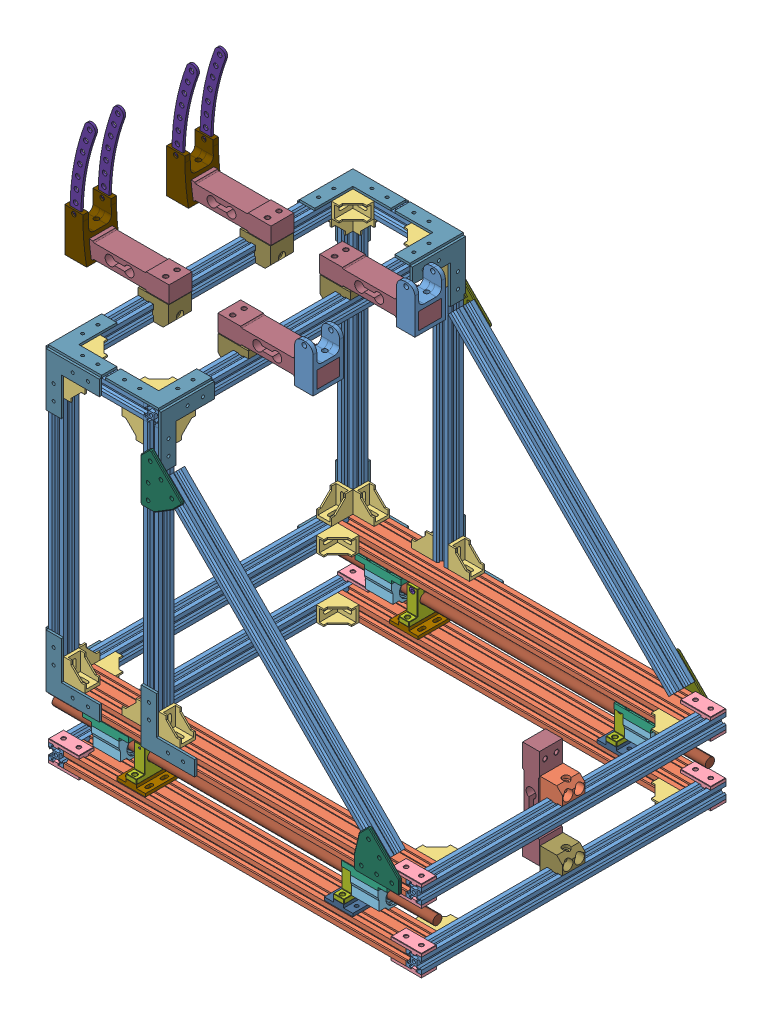
SolidWorks assembly Balança, configuration Valor predeterminado. Lengths in mm.
Overall size (580.64 644.02 408).
129 component instances, 20 part files, 104 mates.
Components (placement in the parent):
- Quadrado_400x490mm-1: Quadrado_400x490mm [Valor predeterminado] at (337.6063 -443.954 467.9915) size (490 20 400)
  - Perfil_20x20mm-3: Perfil_20x20mm [400mm] at (-555.9529 400 -177.9915) x (1 0 0) z (0 -1 0) size (20 400 20)
  - Perfil_20x40mm-2: Perfil_20x40mm [450mm] at (-545.9529 400 -147.9915) x (0 0 -1) z (0 -1 0) size (40 450 20)
  - Perfil_20x40mm-3: Perfil_20x40mm [450mm] at (-545.9529 400 212.0085) x (0 0 -1) z (0 -1 0) size (40 450 20)
  - Perfil_20x20mm-4: Perfil_20x20mm [400mm] at (-85.9529 400 -177.9915) x (1 0 0) z (0 -1 0) size (20 400 20)
  - Cantoneira_interna_20x20mm-1: Cantoneira_interna_20x20mm [Default] at (-95.9529 390 182.0085) x (0 1 0) z (0 0 1) size (20 28 28)
  - Cantoneira_interna_20x20mm-2: Cantoneira_interna_20x20mm [Default] at (-95.9529 410 -137.9915) x (0 -1 0) z (0 0 -1) size (20 28 28)
  - Cantoneira_interna_20x20mm-3: Cantoneira_interna_20x20mm [Default] at (-545.9529 390 -137.9915) x (0 1 0) z (0 0 -1) size (20 28 28)
  - Cantoneira_interna_20x20mm-4: Cantoneira_interna_20x20mm [Default] at (-545.9529 410 182.0085) x (0 -1 0) z (0 0 1) size (20 28 28)
- Quadrado_400x490mm-2: Quadrado_400x490mm [Valor predeterminado] at (337.6063 -364.954 467.9915) size (490 20 400)
  - Perfil_20x20mm-3: Perfil_20x20mm [400mm] at (-555.9529 400 -177.9915) x (1 0 0) z (0 -1 0) size (20 400 20)
  - Perfil_20x40mm-2: Perfil_20x40mm [450mm] at (-545.9529 400 -147.9915) x (0 0 -1) z (0 -1 0) size (40 450 20)
  - Perfil_20x40mm-3: Perfil_20x40mm [450mm] at (-545.9529 400 212.0085) x (0 0 -1) z (0 -1 0) size (40 450 20)
  - Perfil_20x20mm-4: Perfil_20x20mm [400mm] at (-85.9529 400 -177.9915) x (1 0 0) z (0 -1 0) size (20 400 20)
  - Cantoneira_interna_20x20mm-1: Cantoneira_interna_20x20mm [Default] at (-95.9529 390 182.0085) x (0 1 0) z (0 0 1) size (20 28 28)
  - Cantoneira_interna_20x20mm-2: Cantoneira_interna_20x20mm [Default] at (-95.9529 410 -137.9915) x (0 -1 0) z (0 0 -1) size (20 28 28)
  - Cantoneira_interna_20x20mm-3: Cantoneira_interna_20x20mm [Default] at (-545.9529 390 -137.9915) x (0 1 0) z (0 0 -1) size (20 28 28)
  - Cantoneira_interna_20x20mm-4: Cantoneira_interna_20x20mm [Default] at (-545.9529 410 182.0085) x (0 -1 0) z (0 0 1) size (20 28 28)
- Cantoneira_Plana_impressa_20x40mm-17: Cantoneira_Plana_impressa_20x40mm [Valor predeterminado] at (241.6534 -33.954 680) x (0 0 -1) z (1 0 0) size (20 6 40)
- Cantoneira_Plana_impressa_20x40mm-18: Cantoneira_Plana_impressa_20x40mm [Valor predeterminado] at (241.6534 45.046 680) x (0 0 -1) z (1 0 0) size (20 6 40)
- Cantoneira_Plana_impressa_20x40mm-19: Cantoneira_Plana_impressa_20x40mm [Valor predeterminado] at (241.6534 25.046 680) x (0 0 1) z (1 0 0) size (20 6 40)
- Cantoneira_Plana_impressa_20x40mm-20: Cantoneira_Plana_impressa_20x40mm [Valor predeterminado] at (241.6534 -53.954 680) x (0 0 1) z (1 0 0) size (20 6 40)
- Pillow_Block_SC12UU-1: Pillow_Block_SC12UU [Default] at (186.6534 13.046 669) x (0 0 -1) z (1 0 0) size (42 28 36)
- Adaptador_para_Pillow_Block_SC12UU-2: Adaptador_para_Pillow_Block_SC12UU [Valor predeterminado] at (186.6534 17.046 669) size (60 12.59 42.39)
- Suporte_SK12-1: Suporte_SK12 [Valor predeterminado] at (110.9034 -7.9702 663.3047) x (0 0 -1) z (1 0 0) size (42 37.6 14)
  - Shaft support SK12-1: Shaft support SK12 [Valor predeterminado] at (-5.6953 6.0163 42) size (42 37.5 14)
  - m4x16-2: m4x16 [Valor predeterminado] at (4.3047 16.0441 42) x (-1 0 0) z (0 0.924225 0.381849) size (20 7 7)
- Suporte_SK12-3: Suporte_SK12 [Valor predeterminado] at (194.9034 -7.9702 316.6953) x (0 0 1) z (-1 0 0) size (42 37.6 14)
  - Shaft support SK12-1: Shaft support SK12 [Valor predeterminado] at (-5.6953 6.0163 42) size (42 37.5 14)
  - m4x16-2: m4x16 [Valor predeterminado] at (4.3047 16.0441 42) x (-1 0 0) z (0 0.924225 0.381849) size (20 7 7)
- Suporte_SK12-4: Suporte_SK12 [Valor predeterminado] at (-161.5966 -7.9702 663.3047) x (0 0 -1) z (1 0 0) size (42 37.6 14)
  - Shaft support SK12-1: Shaft support SK12 [Valor predeterminado] at (-5.6953 6.0163 42) size (42 37.5 14)
  - m4x16-2: m4x16 [Valor predeterminado] at (4.3047 16.0441 42) x (-1 0 0) z (0 0.924225 0.381849) size (20 7 7)
- Suporte_SK12-5: Suporte_SK12 [Valor predeterminado] at (-77.5966 -7.9702 316.6953) x (0 0 1) z (-1 0 0) size (42 37.6 14)
  - Shaft support SK12-1: Shaft support SK12 [Valor predeterminado] at (-5.6953 6.0163 42) size (42 37.5 14)
  - m4x16-2: m4x16 [Valor predeterminado] at (4.3047 16.0441 42) x (-1 0 0) z (0 0.924225 0.381849) size (20 7 7)
- Adaptador_para_Suporte_SK12_movel-1: Adaptador_para_Suporte_SK12_movel [Valor predeterminado] at (-119.5966 -33.954 669) size (37.5 9 42)
- Adaptador_para_Suporte_SK12_movel-2: Adaptador_para_Suporte_SK12_movel [Valor predeterminado] at (-119.5966 -33.954 311) size (37.5 9 42)
- Adaptador_para_Suporte_SK12_fixo-1: Adaptador_para_Suporte_SK12_fixo [Valor predeterminado] at (152.9034 -33.954 669) size (37.5 9 42)
- Adaptador_para_Suporte_SK12_fixo-3: Adaptador_para_Suporte_SK12_fixo [Valor predeterminado] at (152.9034 -33.954 311) size (37.5 9 42)
- Eixo_Linear_12mm-1: Eixo_Linear_12mm [500mm] at (11.6534 -1.954 669) x (0 -0.455727 -0.89012) z (1 0 0) size (12 12 500)
- Pillow_Block_SC12UU-2: Pillow_Block_SC12UU [Default] at (-153.3466 13.046 669) x (0 0 -1) z (1 0 0) size (42 28 36)
- Pillow_Block_SC12UU-3: Pillow_Block_SC12UU [Default] at (186.6534 13.046 311) x (0 0 1) z (-1 0 0) size (42 28 36)
- Pillow_Block_SC12UU-4: Pillow_Block_SC12UU [Default] at (-153.3466 13.046 311) x (0 0 1) z (-1 0 0) size (42 28 36)
- Adaptador_para_Pillow_Block_SC12UU-3: Adaptador_para_Pillow_Block_SC12UU [Valor predeterminado] at (-153.3466 17.046 669) x (-1 0 0) z (0 0 -1) size (60 12.59 42.39)
- Adaptador_para_Pillow_Block_SC12UU-4: Adaptador_para_Pillow_Block_SC12UU [Valor predeterminado] at (-153.3466 17.046 311) x (-1 0 0) z (0 0 -1) size (60 12.59 42.39)
- Adaptador_para_Pillow_Block_SC12UU-5: Adaptador_para_Pillow_Block_SC12UU [Valor predeterminado] at (186.6534 17.046 311) size (60 12.59 42.39)
- Perfil_20x20mm-1: Perfil_20x20mm [350mm] at (-218.3466 45.046 680) size (20 350 20)
- Perfil_20x20mm-2: Perfil_20x20mm [105mm] at (-103.3466 405.046 680) x (0 1 0) z (0 0 1) size (20 105 20)
- Perfil_20x20mm-3: Perfil_20x20mm [350mm] at (-93.3466 45.046 680) size (20 350 20)
- Perfil_20x20mm-7: Perfil_20x20mm [400mm] at (-218.3466 405.046 290) x (0 1 0) z (1 0 0) size (20 400 20)
- Cantoneira_interna_20x20mm-1: Cantoneira_interna_20x20mm [Default] at (-208.3466 395.046 670) x (0 1 0) z (-1 0 0) size (20 28 28)
- Cantoneira_interna_20x20mm-2: Cantoneira_interna_20x20mm [Default] at (-208.3466 395.046 670) x (0 0 1) z (0 1 0) size (20 28 28)
- Cantoneira_interna_20x20mm-3: Cantoneira_interna_20x20mm [Default] at (-208.3466 395.046 670) x (-1 0 0) z (0 0 1) size (20 28 28)
- Cantoneira_interna_20x20mm-20: Cantoneira_interna_20x20mm [Default] at (-83.3466 45.046 690) x (0 0 -1) z (0 -1 0) size (20 28 28)
- Suporte_para_Celula_de_Carga_Reforcado-1: Suporte_para_Celula_de_Carga_Reforcado [Valor predeterminado] at (-207.1035 412.2907 571.8983) x (0 0 -1) z (1 0 0) size (30 30 40)
- Celula_de_Carga_20kg-1: Celula_de_Carga_20kg [Default] at (-252.8466 436.046 571.8983) x (0 0 -1) z (1 0 0) size (30 22 130)
- Cantoneira_plana_lateral-1: Cantoneira_plana_lateral [Valor predeterminado] at (-228.3466 415.046 693) x (0 0 -1) z (-1 0 0) size (3 70 70)
- Cantoneira_plana_lateral-9: Cantoneira_plana_lateral [Valor predeterminado] at (-228.3466 418.046 690) x (0 -1 0) z (0 0 1) size (3 70 70)
- Cantoneira_plana_lateral-10: Cantoneira_plana_lateral [Valor predeterminado] at (-228.3466 415.046 690) x (-1 0 0) z (0 0 1) size (3 70 70)
- Cantoneira_plana_lateral-19: Cantoneira_plana_lateral [Valor predeterminado] at (-103.3466 25.046 690) x (0 0 1) z (-1 0 0) size (3 70 70)
- Placa_Lateral_45graus_impressa_esquerda-1: Placa_Lateral_45graus_impressa_esquerda [Default] at (254.8514 25.046 690) x (0 0 1) z (-1 0 0) size (6 57.44 60)
- Placa_Lateral_45graus_impressa_esquerda-2: Placa_Lateral_45graus_impressa_esquerda [Default] at (-103.3466 383.2441 690) x (0 0 1) z (0.707107 -0.707107 0) size (6 57.44 60)
- Perfil_20x20mm-10: Perfil_20x20mm [410mm] at (213.6382 52.1171 680) x (0.707107 0.707107 0) z (0 0 1) size (20 410 20)
- Placa_Lateral_45graus_impressa_direita-1: Placa_Lateral_45graus_impressa_direita [Default] at (254.8514 25.046 286) x (0 0 1) z (-1 0 0) size (6 57.44 60)
- Placa_Lateral_45graus_impressa_direita-2: Placa_Lateral_45graus_impressa_direita [Default] at (-103.3466 383.2441 286) x (0 0 1) z (0.707107 -0.707107 0) size (6 57.44 60)
- Montagem_Encaixe_Celula_de_Angulo_Variavel-1: Montagem_Encaixe_Celula_de_Angulo_Variavel [Valor predeterminado] at (-305.8466 447.046 556.8983) x (0 0 1) z (-1 0 0) size (44 166.02 40.37) (flexible)
  - Peça_de_angulo-1: Peça_de_angulo [Default] at (0 51.2431 -0.1062) x (1 0 0) z (0 0.169603 0.985512) size (3 125.28 19.4)
  - Peça_Central-1: Peça_Central [Default] at origin size (44 57 28.72)
  - Peça_de_angulo-2: Peça_de_angulo [Default] at (-37 51.2431 -0.1062) x (1 0 0) z (0 0.169603 0.985512) size (3 125.28 19.4)
- Encaixe_Celula_de_Angulo_Fixo-1: Encaixe_Celula_de_Angulo_Fixo [Default] at (-5.8466 447.046 556.8983) x (0 0 -1) z (1 0 0) size (40 57 24)
- Perfil_20x20mm-11: Perfil_20x20mm [350mm] at (-218.3466 45.046 300) size (20 350 20)
- Perfil_20x20mm-12: Perfil_20x20mm [350mm] at (-93.3466 45.046 300) size (20 350 20)
- Perfil_20x20mm-13: Perfil_20x20mm [105mm] at (-103.3466 405.046 300) x (0 1 0) z (0 0 1) size (20 105 20)
- Eixo_Linear_12mm-3: Eixo_Linear_12mm [500mm] at (11.6534 -1.954 311) x (0 -0.455727 0.89012) z (-1 0 0) size (12 12 500)
- Cantoneira_interna_20x20mm-21: Cantoneira_interna_20x20mm [Default] at (-83.3466 395.046 670) x (-1 0 0) z (0 0 1) size (20 28 28)
- Cantoneira_interna_20x20mm-22: Cantoneira_interna_20x20mm [Default] at (-103.3466 415.046 670) x (0 -1 0) z (1 0 0) size (20 28 28)
- Cantoneira_interna_20x20mm-23: Cantoneira_interna_20x20mm [Default] at (-103.3466 395.046 690) x (0 0 -1) z (0 1 0) size (20 28 28)
- Cantoneira_interna_20x20mm-24: Cantoneira_interna_20x20mm [Default] at (-228.3466 395.046 310) x (1 0 0) z (0 0 -1) size (20 28 28)
- Cantoneira_interna_20x20mm-25: Cantoneira_interna_20x20mm [Default] at (-208.3466 415.046 310) x (0 -1 0) z (-1 0 0) size (20 28 28)
- Cantoneira_interna_20x20mm-26: Cantoneira_interna_20x20mm [Default] at (-208.3466 395.046 290) x (0 0 1) z (0 1 0) size (20 28 28)
- Cantoneira_interna_20x20mm-27: Cantoneira_interna_20x20mm [Default] at (-103.3466 395.046 310) x (0 1 0) z (1 0 0) size (20 28 28)
- Cantoneira_interna_20x20mm-28: Cantoneira_interna_20x20mm [Default] at (-103.3466 395.046 310) x (0 0 -1) z (0 1 0) size (20 28 28)
- Cantoneira_interna_20x20mm-29: Cantoneira_interna_20x20mm [Default] at (-103.3466 395.046 310) x (1 0 0) z (0 0 -1) size (20 28 28)
- Cantoneira_interna_20x20mm-30: Cantoneira_interna_20x20mm [Default] at (-208.3466 45.046 690) x (0 0 -1) z (0 -1 0) size (20 28 28)
- Cantoneira_interna_20x20mm-31: Cantoneira_interna_20x20mm [Default] at (-103.3466 45.046 670) x (0 0 1) z (0 -1 0) size (20 28 28)
- Cantoneira_interna_20x20mm-32: Cantoneira_interna_20x20mm [Default] at (-228.3466 45.046 670) size (20 28 28)
- Cantoneira_interna_20x20mm-33: Cantoneira_interna_20x20mm [Default] at (-208.3466 45.046 310) x (-1 0 0) z (0 0 -1) size (20 28 28)
- Cantoneira_interna_20x20mm-34: Cantoneira_interna_20x20mm [Default] at (-208.3466 45.046 310) x (0 0 -1) z (0 -1 0) size (20 28 28)
- Cantoneira_interna_20x20mm-35: Cantoneira_interna_20x20mm [Default] at (-103.3466 45.046 290) x (0 0 1) z (0 -1 0) size (20 28 28)
- Cantoneira_interna_20x20mm-36: Cantoneira_interna_20x20mm [Default] at (-83.3466 45.046 310) x (0 0 -1) z (0 -1 0) size (20 28 28)
- Perfil_20x20mm-14: Perfil_20x20mm [400mm] at (-93.3466 405.046 290) x (0 1 0) z (1 0 0) size (20 400 20)
- Cantoneira_Plana_impressa_20x40mm-21: Cantoneira_Plana_impressa_20x40mm [Valor predeterminado] at (241.6534 45.046 300) x (0 0 -1) z (1 0 0) size (20 6 40)
- Cantoneira_Plana_impressa_20x40mm-22: Cantoneira_Plana_impressa_20x40mm [Valor predeterminado] at (241.6534 25.046 300) x (0 0 1) z (1 0 0) size (20 6 40)
- Cantoneira_Plana_impressa_20x40mm-23: Cantoneira_Plana_impressa_20x40mm [Valor predeterminado] at (-208.3466 25.046 680) x (0 0 -1) z (-1 0 0) size (20 6 40)
- Cantoneira_Plana_impressa_20x40mm-24: Cantoneira_Plana_impressa_20x40mm [Valor predeterminado] at (-208.3466 25.046 300) x (0 0 -1) z (-1 0 0) size (20 6 40)
- Cantoneira_Plana_impressa_20x40mm-25: Cantoneira_Plana_impressa_20x40mm [Valor predeterminado] at (-208.3466 -33.954 680) x (0 0 1) z (-1 0 0) size (20 6 40)
- Cantoneira_Plana_impressa_20x40mm-26: Cantoneira_Plana_impressa_20x40mm [Valor predeterminado] at (-208.3466 -53.954 680) x (0 0 -1) z (-1 0 0) size (20 6 40)
- Cantoneira_Plana_impressa_20x40mm-27: Cantoneira_Plana_impressa_20x40mm [Valor predeterminado] at (241.6534 -33.954 300) x (0 0 -1) z (1 0 0) size (20 6 40)
- Cantoneira_Plana_impressa_20x40mm-28: Cantoneira_Plana_impressa_20x40mm [Valor predeterminado] at (241.6534 -53.954 300) x (0 0 1) z (1 0 0) size (20 6 40)
- Cantoneira_Plana_impressa_20x40mm-29: Cantoneira_Plana_impressa_20x40mm [Valor predeterminado] at (-208.3466 -53.954 300) x (0 0 -1) z (-1 0 0) size (20 6 40)
- Cantoneira_Plana_impressa_20x40mm-30: Cantoneira_Plana_impressa_20x40mm [Valor predeterminado] at (-208.3466 -33.954 300) x (0 0 1) z (-1 0 0) size (20 6 40)
- Suporte_para_Celula_de_Carga_Reforcado-2: Suporte_para_Celula_de_Carga_Reforcado [Valor predeterminado] at (-104.5898 412.2907 541.8983) x (0 0 1) z (-1 0 0) size (30 30 40)
- Suporte_para_Celula_de_Carga_Reforcado-3: Suporte_para_Celula_de_Carga_Reforcado [Valor predeterminado] at (-207.1035 412.2907 438.1017) x (0 0 -1) z (1 0 0) size (30 30 40)
- Suporte_para_Celula_de_Carga_Reforcado-4: Suporte_para_Celula_de_Carga_Reforcado [Valor predeterminado] at (-104.5898 412.2907 408.1017) x (0 0 1) z (-1 0 0) size (30 30 40)
- Celula_de_Carga_20kg-2: Celula_de_Carga_20kg [Default] at (-58.8466 436.046 571.8983) x (0 0 -1) z (1 0 0) size (30 22 130)
- Celula_de_Carga_20kg-3: Celula_de_Carga_20kg [Default] at (-252.8466 436.046 408.1017) x (0 0 1) z (-1 0 0) size (30 22 130)
- Celula_de_Carga_20kg-4: Celula_de_Carga_20kg [Default] at (-58.8466 436.046 408.1017) x (0 0 1) z (-1 0 0) size (30 22 130)
- Cantoneira_plana_lateral-20: Cantoneira_plana_lateral [Valor predeterminado] at (-228.3466 415.046 290) x (0 0 -1) z (-1 0 0) size (3 70 70)
- Cantoneira_plana_lateral-21: Cantoneira_plana_lateral [Valor predeterminado] at (-228.3466 25.046 690) x (0 0 1) z (-1 0 0) size (3 70 70)
- Cantoneira_plana_lateral-22: Cantoneira_plana_lateral [Valor predeterminado] at (-228.3466 25.046 287) x (0 0 1) z (-1 0 0) size (3 70 70)
- Cantoneira_plana_lateral-23: Cantoneira_plana_lateral [Valor predeterminado] at (-83.3466 415.046 690) x (0 1 0) z (0 0 1) size (3 70 70)
- Cantoneira_plana_lateral-24: Cantoneira_plana_lateral [Valor predeterminado] at (-80.3466 415.046 690) x (-1 0 0) z (0 0 1) size (3 70 70)
- Cantoneira_plana_lateral-25: Cantoneira_plana_lateral [Valor predeterminado] at (-231.3466 415.046 290) x (1 0 0) z (0 0 -1) size (3 70 70)
- Cantoneira_plana_lateral-26: Cantoneira_plana_lateral [Valor predeterminado] at (-228.3466 415.046 290) x (0 1 0) z (0 0 -1) size (3 70 70)
- Cantoneira_plana_lateral-27: Cantoneira_plana_lateral [Valor predeterminado] at (-83.3466 415.046 290) x (1 0 0) z (0 0 -1) size (3 70 70)
- Cantoneira_plana_lateral-28: Cantoneira_plana_lateral [Valor predeterminado] at (-83.3466 418.046 290) x (0 -1 0) z (0 0 -1) size (3 70 70)
- Cantoneira_plana_lateral-29: Cantoneira_plana_lateral [Valor predeterminado] at (-231.3466 25.046 690) size (3 70 70)
- Cantoneira_plana_lateral-30: Cantoneira_plana_lateral [Valor predeterminado] at (-228.3466 25.046 290) x (-1 0 0) z (0 0 -1) size (3 70 70)
- Cantoneira_plana_lateral-31: Cantoneira_plana_lateral [Valor predeterminado] at (-103.3466 25.046 287) x (0 0 1) z (-1 0 0) size (3 70 70)
- Perfil_20x20mm-15: Perfil_20x20mm [410mm] at (213.6382 52.1171 300) x (0.707107 0.707107 0) z (0 0 1) size (20 410 20)
- Montagem_Encaixe_Celula_de_Angulo_Variavel-2: Montagem_Encaixe_Celula_de_Angulo_Variavel [Valor predeterminado] at (-305.8466 447.046 423.1017) x (0 0 1) z (-1 0 0) size (44 166.02 40.37) (flexible)
  - Peça_de_angulo-1: Peça_de_angulo [Default] at (0 51.2431 -0.1062) x (1 0 0) z (0 0.169603 0.985512) size (3 125.28 19.4)
  - Peça_Central-1: Peça_Central [Default] at origin size (44 57 28.72)
  - Peça_de_angulo-2: Peça_de_angulo [Default] at (-37 51.2431 -0.1062) x (1 0 0) z (0 0.169603 0.985512) size (3 125.28 19.4)
- Encaixe_Celula_de_Angulo_Fixo-4: Encaixe_Celula_de_Angulo_Fixo [Default] at (-5.8466 447.046 423.1017) x (0 0 -1) z (1 0 0) size (40 57 24)
- Celula_de_Carga_20kg-5: Celula_de_Carga_20kg [Default] at (220.6534 27.546 475) x (0 0 1) z (0 1 0) size (30 22 130)
- Suporte_para_Celula_de_Carga_Reforcado_ajustavel-2: Suporte_para_Celula_de_Carga_Reforcado_ajustavel [Valor predeterminado] at (244.4087 46.2892 505) x (0 0 -1) z (0 1 0) size (30 30 60)
- Suporte_para_Celula_de_Carga_Reforcado-11: Suporte_para_Celula_de_Carga_Reforcado [Valor predeterminado] at (244.4087 -32.7108 505) x (0 0 -1) z (0 1 0) size (30 30 40)
Mates (geometry in assembly coordinates):
- Coincidente11: coincident aligned: plane of Quadrado_400x490mm-1/Perfil_20x40mm-3 through (241.6534 -33.954 690) normal (0 0 1); plane of Adaptador_para_Suporte_SK12_fixo-1 through (152.9034 -28.954 690) normal (0 0 1)
- Coincidente21: coincident anti-aligned: plane of Quadrado_400x490mm-1/Perfil_20x40mm-3 through (241.6534 -33.954 690) normal (0 1 0); plane of Adaptador_para_Suporte_SK12_fixo-1 through (152.9034 -33.954 669) normal (0 -1 0)
- Distância11: distance = 70 mm anti-aligned: plane of Adaptador_para_Suporte_SK12_fixo-1 through (171.6534 -28.954 669) normal (1 0 0); plane of Quadrado_400x490mm-1/Perfil_20x20mm-4 through (241.6534 -43.954 690) normal (-1 0 0)
- Coincidente51: coincident anti-aligned: plane of Adaptador_para_Suporte_SK12_fixo-1 through (152.9034 -24.954 669) normal (0 1 0); plane of Suporte_SK12-1/Shaft support SK12-1 through (145.9034 -24.954 669) normal (0 -1 0)
- Coincidente91: coincident anti-aligned: plane of Quadrado_400x490mm-1/Perfil_20x40mm-3 through (241.6534 -33.954 676) normal (0 1 0); plane of Adaptador_para_Suporte_SK12_movel-1 through (-119.5966 -33.954 669) normal (0 -1 0)
- Concêntrico11: concentric anti-aligned: cylinder of Suporte_SK12-4/Shaft support SK12-1 through (-126.5966 -1.954 669) axis (1 0 0) radius 6; cylinder of Eixo_Linear_12mm-1 through (261.6534 -1.954 669) axis (-1 0 0) radius 6
- Coincidente111: coincident aligned: plane of Quadrado_400x490mm-1/Perfil_20x20mm-4 through (261.6534 -43.954 690) normal (1 0 0); plane of Eixo_Linear_12mm-1 through (261.6534 -1.954 669) normal (1 0 0)
- Concêntrico31: concentric anti-aligned: cylinder of Eixo_Linear_12mm-1 through (261.6534 -1.954 669) axis (-1 0 0) radius 6; cylinder of Pillow_Block_SC12UU-1 through (216.9287 -1.954 669) axis (1 0 0) radius 6
- Coincidente141: coincident anti-aligned: plane of Pillow_Block_SC12UU-1 through (204.6534 13.046 658) normal (0 1 0); plane of Adaptador_para_Pillow_Block_SC12UU-2 through (186.6534 13.046 669) normal (0 -1 0)
- Concêntrico61: concentric anti-aligned: circle of Pillow_Block_SC12UU-1; cylinder of Adaptador_para_Pillow_Block_SC12UU-2 through (173.6534 25.046 684.25) axis (0 -1 0) radius 2.8
- Concêntrico71: concentric anti-aligned: cylinder of Pillow_Block_SC12UU-1 through (199.6534 13.046 653.75) axis (0 1 0) radius 2.5; cylinder of Adaptador_para_Pillow_Block_SC12UU-2 through (199.6534 25.046 653.75) axis (0 -1 0) radius 2.8
- Coincidente151: coincident aligned: plane of Adaptador_para_Pillow_Block_SC12UU-2 through (186.6534 25.046 690) normal (0 0 1); plane of Quadrado_400x490mm-2/Perfil_20x40mm-3 through (241.6534 45.046 690) normal (0 0 1)
- Coincidente161: coincident aligned: plane of Adaptador_para_Pillow_Block_SC12UU-5 through (186.6534 25.046 290) normal (0 0 -1); plane of Quadrado_400x490mm-2/Perfil_20x40mm-2 through (241.6534 45.046 290) normal (0 0 -1)
- Coincidente171: coincident anti-aligned: plane of Adaptador_para_Pillow_Block_SC12UU-3 through (-153.3466 25.046 669) normal (0 1 0); plane of Quadrado_400x490mm-2/Perfil_20x40mm-3 through (241.6534 25.046 676) normal (0 -1 0)
- Concêntrico91: concentric aligned: cylinder of Adaptador_para_Suporte_SK12_fixo-1 through (152.9034 -28.954 685) axis (0 -1 0) radius 2.8; cylinder of Suporte_SK12-1/Shaft support SK12-1 through (152.9034 12.547 685) axis (0 -1 0) radius 2.75
- Coincidente211: coincident aligned: plane of Quadrado_400x490mm-2/Perfil_20x40mm-3 through (241.6534 45.046 690) normal (0 0 1); plane of Perfil_20x20mm-1 through (-218.3466 395.046 690) normal (0 0 1)
- Coincidente221: coincident aligned: plane of Quadrado_400x490mm-2/Perfil_20x20mm-3 through (-228.3466 35.046 690) normal (-1 0 0); plane of Perfil_20x20mm-1 through (-228.3466 395.046 680) normal (-1 0 0)
- Coincidente231: coincident anti-aligned: plane of Quadrado_400x490mm-2/Perfil_20x20mm-3 through (-218.3466 45.046 690) normal (0 1 0); plane of Perfil_20x20mm-1 through (-218.3466 45.046 680) normal (0 -1 0)
- Coincidente35: coincident aligned: plane of Perfil_20x20mm-1 through (-218.3466 395.046 690) normal (0 0 1); plane of Perfil_20x20mm-2 through (-208.3466 405.046 690) normal (0 0 1)
- Coincidente36: coincident aligned: plane of Perfil_20x20mm-2 through (-208.3466 405.046 690) normal (0 0 1); plane of Perfil_20x20mm-3 through (-93.3466 395.046 690) normal (0 0 1)
- Coincidente38: coincident anti-aligned: plane of Perfil_20x20mm-2 through (-103.3466 405.046 680) normal (1 0 0); plane of Perfil_20x20mm-3 through (-103.3466 395.046 680) normal (-1 0 0)
- Coincidente40: coincident anti-aligned: plane of Perfil_20x20mm-1 through (-208.3466 395.046 680) normal (1 0 0); plane of Perfil_20x20mm-2 through (-208.3466 405.046 680) normal (-1 0 0)
- Coincidente42: coincident aligned: plane of Perfil_20x20mm-1 through (-228.3466 395.046 680) normal (-1 0 0); plane of Perfil_20x20mm-7 through (-228.3466 405.046 690) normal (-1 0 0)
- Coincidente43: coincident aligned: plane of Perfil_20x20mm-1 through (-218.3466 395.046 690) normal (0 0 1); plane of Perfil_20x20mm-7 through (-218.3466 405.046 690) normal (0 0 1)
- Coincidente232: coincident aligned: plane of Perfil_20x20mm-7 through (-218.3466 415.046 690) normal (0 1 0); plane of Cantoneira_interna_20x20mm-1 through (-208.3466 415.046 670) normal (0 1 0)
- Coincidente233: coincident anti-aligned: plane of Perfil_20x20mm-7 through (-208.3466 405.046 690) normal (1 0 0); plane of Cantoneira_interna_20x20mm-1 through (-208.3466 415.046 670) normal (-1 0 0)
- Coincidente234: coincident anti-aligned: plane of Perfil_20x20mm-2 through (-208.3466 405.046 670) normal (0 0 -1); plane of Cantoneira_interna_20x20mm-1 through (-208.3466 415.046 670) normal (0 0 1)
- Coincidente236: coincident aligned: plane of Perfil_20x20mm-1 through (-218.3466 395.046 690) normal (0 0 1); plane of Cantoneira_interna_20x20mm-2 through (-208.3466 395.046 690) normal (0 0 1)
- Coincidente237: coincident anti-aligned: plane of Perfil_20x20mm-1 through (-208.3466 395.046 680) normal (1 0 0); plane of Cantoneira_interna_20x20mm-2 through (-208.3466 395.046 690) normal (-1 0 0)
- Coincidente238: coincident anti-aligned: plane of Perfil_20x20mm-2 through (-208.3466 395.046 680) normal (0 -1 0); plane of Cantoneira_interna_20x20mm-2 through (-208.3466 395.046 690) normal (0 1 0)
- Coincidente240: coincident anti-aligned: plane of Perfil_20x20mm-1 through (-218.3466 395.046 670) normal (0 0 -1); plane of Cantoneira_interna_20x20mm-3 through (-228.3466 395.046 670) normal (0 0 1)
- Coincidente241: coincident anti-aligned: plane of Perfil_20x20mm-7 through (-218.3466 395.046 690) normal (0 -1 0); plane of Cantoneira_interna_20x20mm-3 through (-228.3466 395.046 670) normal (0 1 0)
- Coincidente242: coincident aligned: plane of Perfil_20x20mm-7 through (-228.3466 405.046 690) normal (-1 0 0); plane of Cantoneira_interna_20x20mm-3 through (-228.3466 395.046 670) normal (-1 0 0)
- Coincidente243: coincident anti-aligned: plane of Quadrado_400x490mm-2/Perfil_20x40mm-3 through (241.6534 45.046 690) normal (0 1 0); plane of Cantoneira_interna_20x20mm-20 through (-83.3466 45.046 670) normal (0 -1 0)
- Coincidente244: coincident anti-aligned: plane of Perfil_20x20mm-3 through (-83.3466 395.046 680) normal (1 0 0); plane of Cantoneira_interna_20x20mm-20 through (-83.3466 45.046 670) normal (-1 0 0)
- Coincidente245: coincident aligned: plane of Perfil_20x20mm-3 through (-93.3466 395.046 690) normal (0 0 1); plane of Cantoneira_interna_20x20mm-20 through (-83.3466 45.046 690) normal (0 0 1)
- Coincidente246: coincident anti-aligned: plane of Perfil_20x20mm-1 through (-218.3466 395.046 680) normal (0 1 0); plane of Perfil_20x20mm-7 through (-218.3466 395.046 690) normal (0 -1 0)
- Coincidente247: coincident aligned: plane of Perfil_20x20mm-2 through (-208.3466 415.046 680) normal (0 1 0); plane of Perfil_20x20mm-7 through (-218.3466 415.046 690) normal (0 1 0)
- Coincidente248: coincident anti-aligned: plane of Perfil_20x20mm-2 through (-208.3466 395.046 680) normal (0 -1 0); plane of Perfil_20x20mm-3 through (-93.3466 395.046 680) normal (0 1 0)
- Coincidente256: coincident aligned: plane of Cantoneira_Plana_impressa_20x40mm-18 through (261.6534 49.046 690) normal (1 0 0); plane of Quadrado_400x490mm-2/Perfil_20x20mm-4 through (261.6534 35.046 690) normal (1 0 0)
- Coincidente257: coincident anti-aligned: plane of Quadrado_400x490mm-2/Perfil_20x40mm-3 through (241.6534 45.046 690) normal (0 1 0); plane of Cantoneira_Plana_impressa_20x40mm-18 through (241.6534 45.046 680) normal (0 -1 0)
- Coincidente258: coincident aligned: plane of Quadrado_400x490mm-2/Perfil_20x40mm-3 through (241.6534 45.046 690) normal (0 0 1); plane of Cantoneira_Plana_impressa_20x40mm-18 through (221.6534 49.046 690) normal (0 0 1)
- Distância33: distance = 25 mm anti-aligned: plane of Adaptador_para_Pillow_Block_SC12UU-2 through (216.6534 25.046 669) normal (1 0 0); plane of Quadrado_400x490mm-2/Perfil_20x20mm-4 through (241.6534 35.046 690) normal (-1 0 0)
- Coincidente261: coincident aligned: plane of Quadrado_400x490mm-1/Perfil_20x20mm-4 through (261.6534 -43.954 690) normal (1 0 0); plane of Quadrado_400x490mm-2/Perfil_20x20mm-4 through (261.6534 35.046 690) normal (1 0 0)
- Coincidente268: coincident aligned: plane of Quadrado_400x490mm-2/Perfil_20x20mm-4 through (261.6534 35.046 690) normal (1 0 0); plane of Cantoneira_Plana_impressa_20x40mm-19 through (261.6534 21.046 670) normal (1 0 0)
- Coincidente269: coincident aligned: plane of Quadrado_400x490mm-2/Perfil_20x40mm-3 through (241.6534 31.046 690) normal (0 0 1); plane of Cantoneira_Plana_impressa_20x40mm-19 through (221.6534 21.046 690) normal (0 0 1)
- Coincidente270: coincident anti-aligned: plane of Quadrado_400x490mm-2/Perfil_20x40mm-3 through (241.6534 25.046 690) normal (0 -1 0); plane of Cantoneira_Plana_impressa_20x40mm-19 through (241.6534 25.046 680) normal (0 1 0)
- Coincidente271: coincident aligned: plane of Quadrado_400x490mm-1/Perfil_20x40mm-3 through (241.6534 -33.954 690) normal (0 0 1); plane of Cantoneira_Plana_impressa_20x40mm-17 through (221.6534 -29.954 690) normal (0 0 1)
- Coincidente272: coincident aligned: plane of Quadrado_400x490mm-1/Perfil_20x40mm-3 through (241.6534 -47.954 690) normal (0 0 1); plane of Cantoneira_Plana_impressa_20x40mm-20 through (221.6534 -57.954 690) normal (0 0 1)
- Coincidente273: coincident aligned: plane of Quadrado_400x490mm-1/Perfil_20x20mm-4 through (261.6534 -43.954 690) normal (1 0 0); plane of Cantoneira_Plana_impressa_20x40mm-20 through (261.6534 -57.954 670) normal (1 0 0)
- Coincidente274: coincident aligned: plane of Quadrado_400x490mm-1/Perfil_20x20mm-4 through (261.6534 -43.954 690) normal (1 0 0); plane of Cantoneira_Plana_impressa_20x40mm-17 through (261.6534 -29.954 690) normal (1 0 0)
- Coincidente275: coincident anti-aligned: plane of Quadrado_400x490mm-1/Perfil_20x40mm-3 through (241.6534 -33.954 690) normal (0 1 0); plane of Cantoneira_Plana_impressa_20x40mm-17 through (241.6534 -33.954 680) normal (0 -1 0)
- Coincidente276: coincident anti-aligned: plane of Quadrado_400x490mm-1/Perfil_20x40mm-3 through (241.6534 -53.954 690) normal (0 -1 0); plane of Cantoneira_Plana_impressa_20x40mm-20 through (241.6534 -53.954 680) normal (0 1 0)
- Coincidente277: coincident anti-aligned: plane of Perfil_20x20mm-7 through (-208.3466 405.046 690) normal (1 0 0); plane of Suporte_para_Celula_de_Carga_Reforcado-1 through (-208.3466 412.2907 541.8983) normal (-1 0 0)
- Coincidente278: coincident anti-aligned: plane of Perfil_20x20mm-7 through (-218.3466 415.046 690) normal (0 1 0); plane of Suporte_para_Celula_de_Carga_Reforcado-1 through (-207.1035 415.046 541.8983) normal (0 -1 0)
- Concêntrico93: concentric aligned: cylinder of Suporte_para_Celula_de_Carga_Reforcado-1 through (-199.8466 395.045 564.3983) axis (0 1 0) radius 3.25; cylinder of Celula_de_Carga_20kg-1 through (-199.8466 425.046 564.3983) axis (0 1 0) radius 2.75
- Concêntrico94: concentric aligned: cylinder of Suporte_para_Celula_de_Carga_Reforcado-1 through (-199.8466 395.045 549.3983) axis (0 1 0) radius 3.25; cylinder of Celula_de_Carga_20kg-1 through (-199.8466 425.046 549.3983) axis (0 1 0) radius 2.75
- Coincidente279: coincident anti-aligned: plane of Suporte_para_Celula_de_Carga_Reforcado-1 through (-207.1035 425.046 541.8983) normal (0 1 0); plane of Celula_de_Carga_20kg-1 through (-252.8466 425.046 541.8983) normal (0 -1 0)
- Concêntrico95: concentric aligned: cylinder of Suporte_SK12-4/Shaft support SK12-1 through (-119.5966 12.547 685) axis (0 -1 0) radius 2.75; cylinder of Adaptador_para_Suporte_SK12_movel-1 through (-119.5966 -28.954 685) axis (0 -1 0) radius 2.8
- Concêntrico96: concentric aligned: cylinder of Suporte_SK12-4/Shaft support SK12-1 through (-119.5966 12.547 653) axis (0 -1 0) radius 2.75; cylinder of Adaptador_para_Suporte_SK12_movel-1 through (-119.5966 -28.954 653) axis (0 -1 0) radius 2.8
- Coincidente280: coincident anti-aligned: plane of Perfil_20x20mm-2 through (-208.3466 405.046 690) normal (0 0 1); plane of Cantoneira_plana_lateral-1 through (-228.3466 415.046 690) normal (0 0 -1)
- Coincidente281: coincident aligned: plane of Perfil_20x20mm-2 through (-208.3466 415.046 680) normal (0 1 0); plane of Cantoneira_plana_lateral-1 through (-228.3466 415.046 690) normal (0 1 0)
- Coincidente282: coincident aligned: plane of Perfil_20x20mm-7 through (-228.3466 405.046 690) normal (-1 0 0); plane of Cantoneira_plana_lateral-1 through (-228.3466 415.046 690) normal (-1 0 0)
- Coincidente283: coincident anti-aligned: plane of Perfil_20x20mm-7 through (-218.3466 415.046 690) normal (0 1 0); plane of Cantoneira_plana_lateral-9 through (-228.3466 415.046 690) normal (0 -1 0)
- Coincidente284: coincident aligned: plane of Perfil_20x20mm-2 through (-208.3466 405.046 690) normal (0 0 1); plane of Cantoneira_plana_lateral-9 through (-228.3466 415.046 690) normal (0 0 1)
- Coincidente285: coincident aligned: plane of Perfil_20x20mm-7 through (-228.3466 405.046 690) normal (-1 0 0); plane of Cantoneira_plana_lateral-9 through (-228.3466 415.046 690) normal (-1 0 0)
- Coincidente288: coincident anti-aligned: plane of Perfil_20x20mm-7 through (-228.3466 405.046 690) normal (-1 0 0); plane of Cantoneira_plana_lateral-10 through (-228.3466 415.046 690) normal (1 0 0)
- Coincidente289: coincident aligned: plane of Perfil_20x20mm-7 through (-218.3466 415.046 690) normal (0 1 0); plane of Cantoneira_plana_lateral-10 through (-231.3466 415.046 690) normal (0 1 0)
- Coincidente290: coincident aligned: plane of Perfil_20x20mm-1 through (-218.3466 395.046 690) normal (0 0 1); plane of Cantoneira_plana_lateral-10 through (-231.3466 415.046 690) normal (0 0 1)
- Coincidente291: coincident anti-aligned: plane of Quadrado_400x490mm-2/Perfil_20x40mm-3 through (241.6534 45.046 690) normal (0 0 1); plane of Cantoneira_plana_lateral-19 through (-103.3466 25.046 690) normal (0 0 -1)
- Coincidente292: coincident aligned: plane of Perfil_20x20mm-3 through (-103.3466 395.046 680) normal (-1 0 0); plane of Cantoneira_plana_lateral-19 through (-103.3466 25.046 693) normal (-1 0 0)
- Coincidente293: coincident aligned: plane of Quadrado_400x490mm-2/Perfil_20x40mm-3 through (241.6534 25.046 690) normal (0 -1 0); plane of Cantoneira_plana_lateral-19 through (-103.3466 25.046 693) normal (0 -1 0)
- Coincidente294: coincident anti-aligned: plane of Quadrado_400x490mm-2/Perfil_20x40mm-3 through (241.6534 45.046 690) normal (0 0 1); plane of Placa_Lateral_45graus_impressa_esquerda-1 through (254.8514 25.046 690) normal (0 0 -1)
- Coincidente295: coincident aligned: plane of Quadrado_400x490mm-2/Perfil_20x40mm-3 through (241.6534 25.046 690) normal (0 -1 0); plane of Placa_Lateral_45graus_impressa_esquerda-1 through (176.7113 25.046 694) normal (0 -1 0)
- Coincidente296: coincident aligned: plane of Perfil_20x20mm-3 through (-103.3466 395.046 680) normal (-1 0 0); plane of Placa_Lateral_45graus_impressa_esquerda-2 through (-103.3466 357.5901 694) normal (-1 0 0)
- Coincidente297: coincident anti-aligned: plane of Perfil_20x20mm-3 through (-93.3466 395.046 690) normal (0 0 1); plane of Placa_Lateral_45graus_impressa_esquerda-2 through (-103.3466 383.2441 690) normal (0 0 -1)
- Coincidente298: coincident aligned: plane of Perfil_20x20mm-3 through (-93.3466 395.046 690) normal (0 0 1); plane of Perfil_20x20mm-10 through (-76.2756 342.0309 690) normal (0 0 1)
- Coincidente299: coincident aligned: plane of Placa_Lateral_45graus_impressa_esquerda-2 through (-48.0932 327.9907 694) normal (0.707107 0.707107 0); plane of Perfil_20x20mm-10 through (-69.2045 349.1019 680) normal (0.707107 0.707107 0)
- Coincidente300: coincident aligned: plane of Placa_Lateral_45graus_impressa_esquerda-1 through (236.7113 43.1861 694) normal (0.707107 0.707107 0); plane of Perfil_20x20mm-10 through (-69.2045 349.1019 680) normal (0.707107 0.707107 0)
- Coincidente301: coincident: plane of Quadrado_400x490mm-2/Perfil_20x40mm-3 through (241.6534 45.046 690) normal (0 1 0); line of Perfil_20x20mm-10 through (206.5672 45.046 684.6984) axis (0 0 1)
- Coincidente302: coincident: plane of Perfil_20x20mm-3 through (-83.3466 395.046 680) normal (1 0 0); line of Perfil_20x20mm-10 through (-83.3466 334.9598 670) axis (0 0 1)
- Coincidente303: coincident aligned: plane of Perfil_20x20mm-15 through (-69.2045 349.1019 300) normal (0.707107 0.707107 0); plane of Placa_Lateral_45graus_impressa_direita-1 through (236.7113 43.1861 290) normal (0.707107 0.707107 0)
- Coincidente304: coincident aligned: plane of Quadrado_400x490mm-2/Perfil_20x40mm-2 through (241.6534 25.046 290) normal (0 -1 0); plane of Placa_Lateral_45graus_impressa_direita-1 through (176.7113 25.046 290) normal (0 -1 0)
- Coincidente305: coincident anti-aligned: plane of Perfil_20x20mm-15 through (-76.2756 342.0309 290) normal (0 0 -1); plane of Placa_Lateral_45graus_impressa_direita-1 through (254.8514 25.046 290) normal (0 0 1)
- Coincidente306: coincident aligned: plane of Perfil_20x20mm-12 through (-103.3466 395.046 300) normal (-1 0 0); plane of Placa_Lateral_45graus_impressa_direita-2 through (-103.3466 357.5901 290) normal (-1 0 0)
- Coincidente307: coincident aligned: plane of Perfil_20x20mm-15 through (-69.2045 349.1019 300) normal (0.707107 0.707107 0); plane of Placa_Lateral_45graus_impressa_direita-2 through (-48.0932 327.9907 290) normal (0.707107 0.707107 0)
- Coincidente308: coincident anti-aligned: plane of Perfil_20x20mm-12 through (-93.3466 395.046 290) normal (0 0 -1); plane of Placa_Lateral_45graus_impressa_direita-2 through (-103.3466 383.2441 290) normal (0 0 1)
- Coincidente317: coincident anti-aligned: plane of Celula_de_Carga_20kg-1 through (-252.8466 425.046 541.8983) normal (0 -1 0); plane of Montagem_Encaixe_Celula_de_Angulo_Variavel-1/Peça_Central-1 through (-305.8466 425.046 556.8983) normal (0 1 0)
- Concêntrico100: concentric anti-aligned: cylinder of Celula_de_Carga_20kg-1 through (-305.8466 425.046 549.3983) axis (0 1 0) radius 2.75; cylinder of Montagem_Encaixe_Celula_de_Angulo_Variavel-1/Peça_Central-1 through (-305.8466 477.046 549.3983) axis (0 -1 0) radius 3.2
- Coincidente320: coincident anti-aligned: plane of Celula_de_Carga_20kg-2 through (-58.8466 425.046 541.8983) normal (0 -1 0); plane of Encaixe_Celula_de_Angulo_Fixo-1 through (-5.8466 425.046 556.8983) normal (0 1 0)
- Coincidente321: coincident anti-aligned: plane of Celula_de_Carga_20kg-2 through (-58.8466 436.046 541.8983) normal (0 0 -1); plane of Encaixe_Celula_de_Angulo_Fixo-1 through (-5.8466 447.046 541.8983) normal (0 0 1)
- Concêntrico101: concentric anti-aligned: cylinder of Celula_de_Carga_20kg-2 through (-5.8466 425.046 549.3983) axis (0 1 0) radius 2.75; cylinder of Encaixe_Celula_de_Angulo_Fixo-1 through (-5.8466 477.046 549.3983) axis (0 -1 0) radius 3.2
- Concêntrico104: concentric anti-aligned: cylinder of Celula_de_Carga_20kg-1 through (-305.8466 425.046 564.3983) axis (0 1 0) radius 2.75; cylinder of Montagem_Encaixe_Celula_de_Angulo_Variavel-1/Peça_Central-1 through (-305.8466 477.046 564.3983) axis (0 -1 0) radius 3.2
- Concêntrico105: concentric aligned: cylinder of Montagem_Encaixe_Celula_de_Angulo_Variavel-1/Peça_de_angulo-1 through (-287.198 576.1681 573.8983) axis (0 0 1) radius 3; cylinder of Montagem_Encaixe_Celula_de_Angulo_Variavel-2/Peça_de_angulo-1 through (-287.198 576.1681 440.1017) axis (0 0 1) radius 3
- Coincidente348: coincident anti-aligned: plane of Celula_de_Carga_20kg-5 through (231.6534 27.546 505) normal (1 0 0); plane of Suporte_para_Celula_de_Carga_Reforcado_ajustavel-2 through (231.6534 46.2892 475) normal (-1 0 0)
- Coincidente355: coincident aligned: plane of Celula_de_Carga_20kg-5 through (220.6534 27.546 475) normal (0 0 -1); plane of Suporte_para_Celula_de_Carga_Reforcado_ajustavel-2 through (244.4087 46.2892 475) normal (0 0 -1)
- Coincidente358: coincident aligned: plane of Suporte_para_Celula_de_Carga_Reforcado_ajustavel-2 through (244.4087 46.2892 475) normal (0 0 -1); plane of Suporte_para_Celula_de_Carga_Reforcado-11 through (244.4087 -32.7108 475) normal (0 0 -1)
- Concêntrico129: concentric anti-aligned: cylinder of Celula_de_Carga_20kg-5 through (209.6534 -25.454 482.5) axis (1 0 0) radius 2.75; cylinder of Suporte_para_Celula_de_Carga_Reforcado-11 through (261.6544 -25.454 482.5) axis (-1 0 0) radius 3.25
- Concêntrico130: concentric anti-aligned: cylinder of Celula_de_Carga_20kg-5 through (209.6534 -25.454 497.5) axis (1 0 0) radius 2.75; cylinder of Suporte_para_Celula_de_Carga_Reforcado-11 through (261.6544 -25.454 497.5) axis (-1 0 0) radius 3.25
- Coincidente359: coincident anti-aligned: plane of Celula_de_Carga_20kg-5 through (231.6534 27.546 505) normal (1 0 0); plane of Suporte_para_Celula_de_Carga_Reforcado-11 through (231.6534 -32.7108 475) normal (-1 0 0)
- Coincidente360: coincident anti-aligned: plane of Quadrado_400x490mm-2/Perfil_20x20mm-4 through (251.6534 45.046 690) normal (0 1 0); plane of Suporte_para_Celula_de_Carga_Reforcado_ajustavel-2 through (244.4087 45.046 475) normal (0 -1 0)
- Coincidente361: coincident anti-aligned: plane of Quadrado_400x490mm-2/Perfil_20x20mm-4 through (241.6534 35.046 690) normal (-1 0 0); plane of Suporte_para_Celula_de_Carga_Reforcado_ajustavel-2 through (241.6534 46.2892 475) normal (1 0 0)
- Coincidente362: coincident anti-aligned: plane of Quadrado_400x490mm-1/Perfil_20x20mm-4 through (251.6534 -33.954 690) normal (0 1 0); plane of Suporte_para_Celula_de_Carga_Reforcado-11 through (244.4087 -33.954 475) normal (0 -1 0)
- Simétrico1: symmetric aligned: plane of Suporte_para_Celula_de_Carga_Reforcado_ajustavel-2 through (244.4087 46.2892 505) normal (0 0 1); plane of Suporte_para_Celula_de_Carga_Reforcado_ajustavel-2 through (244.4087 46.2892 475) normal (0 0 -1); plane of assembly through (0 0 490) normal (0 0 1)
